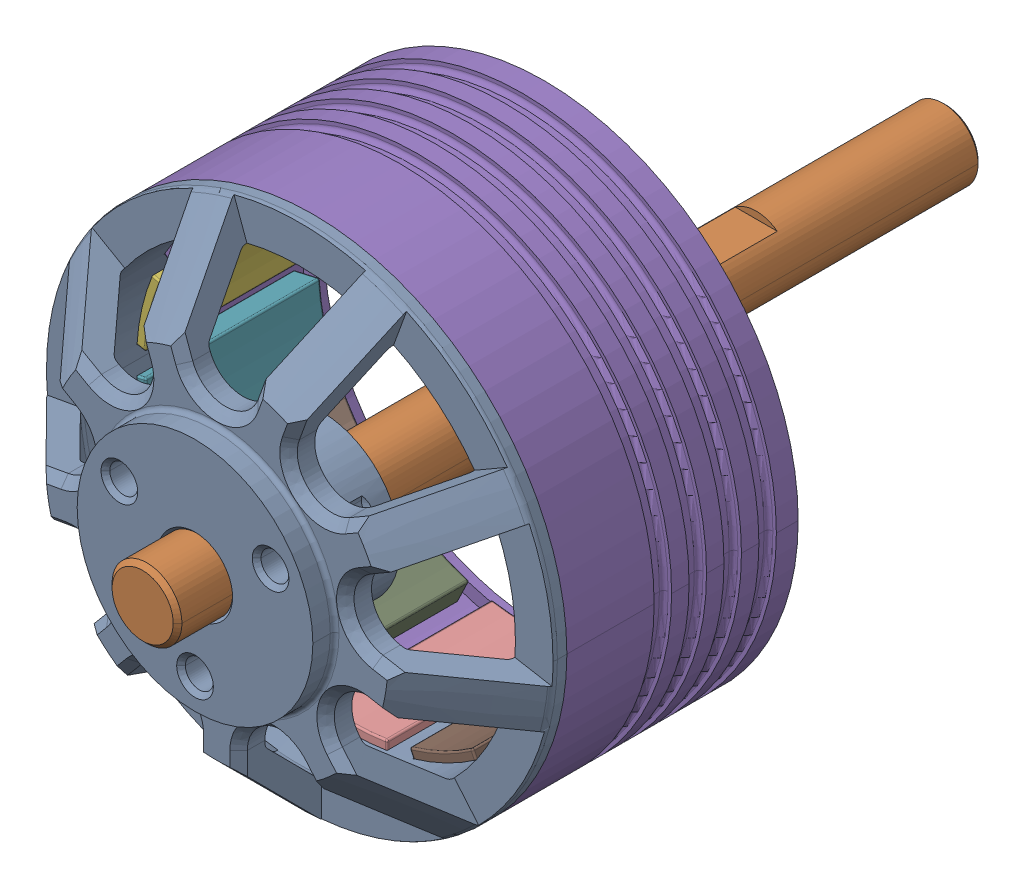
SolidWorks assembly 2310-Rotor-Assem.STEP, configuration Default. Lengths in mm.
Overall size (29.1 29.1 46).
17 component instances, 4 part files, 0 mates.
Components (placement in the parent):
- 23mm-Endbell.STEP-1: 23mm-Endbell.STEP [Default] at (-57.7218 14.2616 14.8949) size (29.1 29.1 12.75)
- 2310-Shaft.STEP-1: 2310-Shaft.STEP [Default] at (-57.7218 14.2616 -15.3551) size (4 4 46)
- 2310-Magnet.STEP-1: 2310-Magnet.STEP [Default] at (-57.7218 14.2616 8.6449) size (4 1.65 10)
- 2310-Magnet.STEP-2: 2310-Magnet.STEP [Default] at (-57.7218 14.2616 8.6449) x (0.900969 0.433884 0) z (0 0 1) size (4 1.65 10)
- 2310-Magnet.STEP-3: 2310-Magnet.STEP [Default] at (-57.7218 14.2616 8.6449) x (0.62349 0.781831 0) z (0 0 1) size (4 1.65 10)
- 2310-Magnet.STEP-4: 2310-Magnet.STEP [Default] at (-57.7218 14.2616 8.6449) x (0.222521 0.974928 0) z (0 0 1) size (4 1.65 10)
- 2310-Magnet.STEP-5: 2310-Magnet.STEP [Default] at (-57.7218 14.2616 8.6449) x (-0.222521 0.974928 0) z (0 0 1) size (4 1.65 10)
- 2310-Magnet.STEP-6: 2310-Magnet.STEP [Default] at (-57.7218 14.2616 8.6449) x (-0.62349 0.781831 0) z (0 0 1) size (4 1.65 10)
- 2310-Magnet.STEP-7: 2310-Magnet.STEP [Default] at (-57.7218 14.2616 8.6449) x (-0.900969 0.433884 0) z (0 0 1) size (4 1.65 10)
- 2310-Magnet.STEP-8: 2310-Magnet.STEP [Default] at (-57.7218 14.2616 8.6449) x (-1 0 0) z (0 0 1) size (4 1.65 10)
- 2310-Magnet.STEP-9: 2310-Magnet.STEP [Default] at (-57.7218 14.2616 8.6449) x (-0.900969 -0.433884 0) z (0 0 1) size (4 1.65 10)
- 2310-Magnet.STEP-10: 2310-Magnet.STEP [Default] at (-57.7218 14.2616 8.6449) x (-0.62349 -0.781831 0) z (0 0 1) size (4 1.65 10)
- 2310-Magnet.STEP-11: 2310-Magnet.STEP [Default] at (-57.7218 14.2616 8.6449) x (-0.222521 -0.974928 0) z (0 0 1) size (4 1.65 10)
- 2310-Magnet.STEP-12: 2310-Magnet.STEP [Default] at (-57.7218 14.2616 8.6449) x (0.222521 -0.974928 0) z (0 0 1) size (4 1.65 10)
- 2310-Magnet.STEP-13: 2310-Magnet.STEP [Default] at (-57.7218 14.2616 8.6449) x (0.62349 -0.781831 0) z (0 0 1) size (4 1.65 10)
- 2310-Magnet.STEP-14: 2310-Magnet.STEP [Default] at (-57.7218 14.2616 8.6449) x (0.900969 -0.433884 0) z (0 0 1) size (4 1.65 10)
- 2310-Fluxring.STEP-1: 2310-Fluxring.STEP [Default] at (-57.7218 14.2616 7.6449) size (29.1 29.1 13.25)
